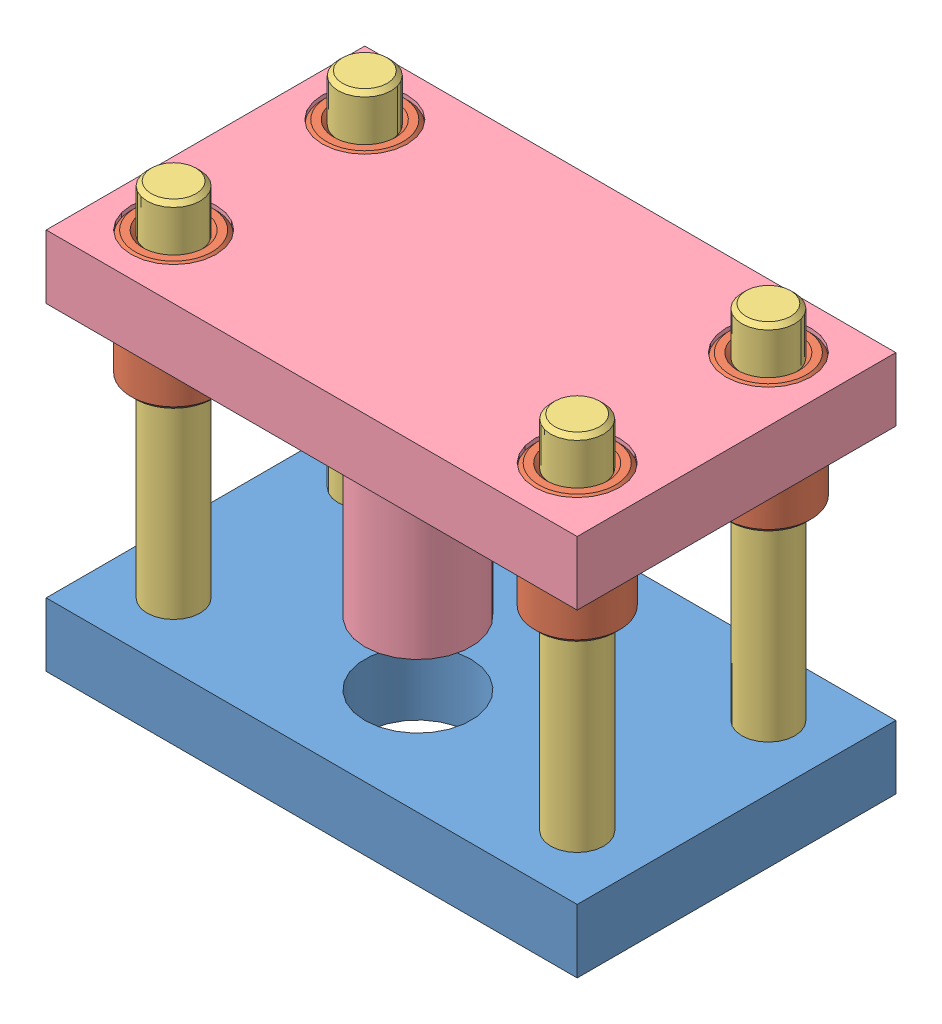
SolidWorks assembly Assem2, configuration Default. Lengths in mm.
Overall size (250 200 150).
10 component instances, 4 part files, 7 mates.
Components (placement in the parent):
- Bottom Plate-1: Bottom Plate [Default] at (129.3995 123.4478 204.6233) x (-1 0 0) z (0 0 1) size (250 30 150)
- Guide Bush-1: Guide Bush [Default] at (34.3995 258.4478 222.6233) x (0.996904 0 0.078629) z (-0.078629 0 0.996904) size (40 60 40)
- Guide Pillar-1: Guide Pillar [Default] at (34.3995 208.4478 222.6233) size (25 200 25)
- Top Plate-1: Top Plate [Default] at (167.8814 273.4478 161.1698) x (-1 0 0) z (0 0 1) size (250 120 150)
- Guide Bush-2: Guide Bush [Default] at (224.3995 258.4478 222.6233) x (0.996904 0 0.078629) z (-0.078629 0 0.996904) size (40 60 40)
- Guide Bush-3: Guide Bush [Default] at (34.3995 258.4478 132.6233) x (0.996904 0 0.078629) z (-0.078629 0 0.996904) size (40 60 40)
- Guide Bush-4: Guide Bush [Default] at (224.3995 258.4478 132.6233) x (0.996904 0 0.078629) z (-0.078629 0 0.996904) size (40 60 40)
- Guide Pillar-2: Guide Pillar [Default] at (224.3995 208.4478 222.6233) size (25 200 25)
- Guide Pillar-3: Guide Pillar [Default] at (34.3995 208.4478 132.6233) size (25 200 25)
- Guide Pillar-4: Guide Pillar [Default] at (224.3995 208.4478 132.6233) size (25 200 25)
Mates (geometry in assembly coordinates):
- Concentric1: concentric aligned: cylinder of Guide Bush-1 through (34.3995 288.4478 222.6233) axis (0 -1 0) radius 12.5; cylinder of Guide Pillar-1 through (34.3995 308.4478 222.6233) axis (0 -1 0) radius 12.5
- Coincident1: coincident aligned: circle of Bottom Plate-1; plane of Guide Pillar-1 through (34.3995 108.4478 222.6233) normal (0 -1 0)
- Concentric2: concentric anti-aligned: cylinder of Bottom Plate-1 through (34.3995 108.4478 222.6233) axis (0 1 0) radius 12.5; cylinder of Guide Pillar-1 through (34.3995 308.4478 222.6233) axis (0 -1 0) radius 12.5
- Concentric3: concentric aligned: cylinder of Bottom Plate-1 through (129.3995 108.4478 202.6233) axis (0 1 0) radius 25; cylinder of Top Plate-1 through (129.3995 168.4478 202.6233) axis (0 1 0) radius 25
- Coincident2: coincident aligned: plane of Guide Bush-1 through (34.3995 288.4478 222.6233) normal (0 1 0); plane of Top Plate-1 through (167.8814 288.4478 161.1698) normal (0 1 0)
- Concentric4: concentric anti-aligned: cylinder of Guide Bush-1 through (34.3995 288.4478 222.6233) axis (0 -1 0) radius 20; cylinder of Top Plate-1 through (34.3995 258.4478 222.6233) axis (0 1 0) radius 20
- Distance1: distance = 20 mm aligned: plane of Top Plate-1 through (167.8814 288.4478 161.1698) normal (0 1 0); plane of Guide Pillar-1 through (34.3995 308.4478 222.6233) normal (0 1 0)
